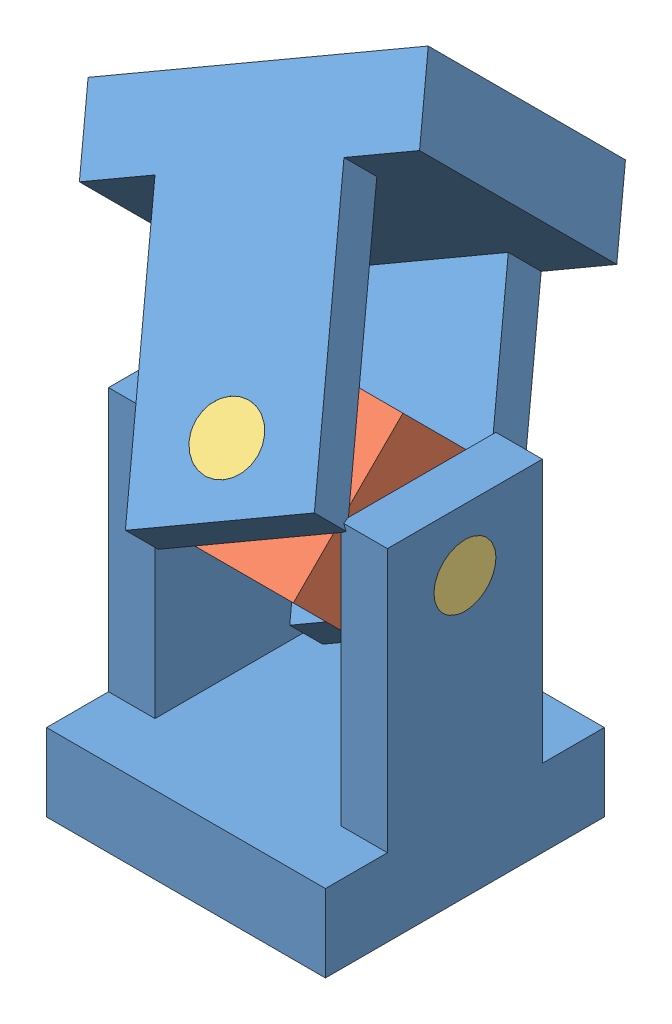
SolidWorks assembly U-Bracket Fully Assembled, configuration Default. Lengths in mm.
Overall size (132.94 192.84 162.82).
7 component instances, 3 part files, 14 mates.
Components (placement in the parent):
- U-Bracket-1: U-Bracket [Default] at (-39.6126 -81.0494 38.6006) size (90 110 90)
- Square Block-1: Square Block [Default] at (-39.6126 8.9506 38.6006) x (1 0 0) z (0 0.707107 0.707107) size (50 50 50)
- Pin-1: Pin [Default] at (-9.6126 8.9506 38.6006) size (30 20 20)
- Pin-2: Pin [Default] at (-69.6126 8.9506 38.6006) size (30 20 20)
- Pin-3: Pin [Default] at (-39.6126 30.1638 59.8138) x (0 -0.707107 -0.707107) z (1 0 0) size (30 20 20)
- Pin-4: Pin [Default] at (-39.6126 -12.2626 17.3874) x (0 -0.707107 -0.707107) z (1 0 0) size (30 20 20)
- U-Bracket-2: U-Bracket [Default] at (-84.6126 64.0641 -16.5129) x (0 0.707107 0.707107) z (0.866025 0.353553 -0.353553) size (90 110 90)
Mates (geometry in assembly coordinates):
- Coincident1: coincident anti-aligned: plane of Square Block-1 through (-24.6126 8.9506 38.6006) normal (1 0 0); plane of Pin-1 through (-24.6126 8.9506 38.6006) normal (-1 0 0)
- Concentric1: concentric anti-aligned: cylinder of Square Block-1 through (-24.6126 8.9506 38.6006) axis (1 0 0) radius 10; cylinder of Pin-1 through (5.3874 8.9506 38.6006) axis (-1 0 0) radius 10
- Coincident2: coincident anti-aligned: plane of Square Block-1 through (-54.6126 8.9506 38.6006) normal (-1 0 0); plane of Pin-2 through (-54.6126 8.9506 38.6006) normal (1 0 0)
- Concentric2: concentric aligned: cylinder of Square Block-1 through (-54.6126 8.9506 38.6006) axis (-1 0 0) radius 10; cylinder of Pin-2 through (-54.6126 8.9506 38.6006) axis (-1 0 0) radius 10
- Coincident3: coincident anti-aligned: plane of Square Block-1 through (-39.6126 19.5572 49.2072) normal (0 0.707107 0.707107); plane of Pin-3 through (-39.6126 19.5572 49.2072) normal (0 -0.707107 -0.707107)
- Concentric3: concentric aligned: cylinder of Square Block-1 through (-39.6126 19.5572 49.2072) axis (0 0.707107 0.707107) radius 10; cylinder of Pin-3 through (-39.6126 19.5572 49.2072) axis (0 0.707107 0.707107) radius 10
- Coincident4: coincident anti-aligned: plane of Square Block-1 through (-39.6126 -1.656 27.994) normal (0 -0.707107 -0.707107); plane of Pin-4 through (-39.6126 -1.656 27.994) normal (0 0.707107 0.707107)
- Concentric4: concentric anti-aligned: cylinder of Square Block-1 through (-39.6126 -1.656 27.994) axis (0 -0.707107 -0.707107) radius 10; cylinder of Pin-4 through (-39.6126 -22.8692 6.7808) axis (0 0.707107 0.707107) radius 10
- Coincident5: coincident aligned: plane of U-Bracket-1 through (5.3874 -81.0494 38.6006) normal (1 0 0); plane of Pin-1 through (5.3874 8.9506 38.6006) normal (1 0 0)
- Concentric5: concentric anti-aligned: cylinder of U-Bracket-1 through (-84.6126 8.9506 38.6006) axis (1 0 0) radius 10; cylinder of Pin-1 through (5.3874 8.9506 38.6006) axis (-1 0 0) radius 10
- Coincident7: coincident aligned: plane of Pin-3 through (-39.6126 40.7704 70.4204) normal (0 0.707107 0.707107); plane of U-Bracket-2 through (5.3874 95.884 15.3069) normal (0 0.707107 0.707107)
- Concentric6: concentric aligned: cylinder of Pin-3 through (-39.6126 19.5572 49.2072) axis (0 0.707107 0.707107) radius 10; cylinder of U-Bracket-2 through (-39.6126 -22.8692 6.7808) axis (0 0.707107 0.707107) radius 10
- Angle1: planar angle = 0.785398 rad aligned: plane of Square Block-1 through (-14.6126 44.306 38.6006) normal (0 0.707107 -0.707107); plane of U-Bracket-1 through (5.3874 28.9506 13.6006) normal (0 1 0)
- Angle2: planar angle = 1.047198 rad aligned: plane of U-Bracket-2 through (-7.9619 37.3618 73.829) normal (0.866025 0.353553 -0.353553); plane of Square Block-1 through (-14.6126 44.306 38.6006) normal (0 0.707107 -0.707107)
